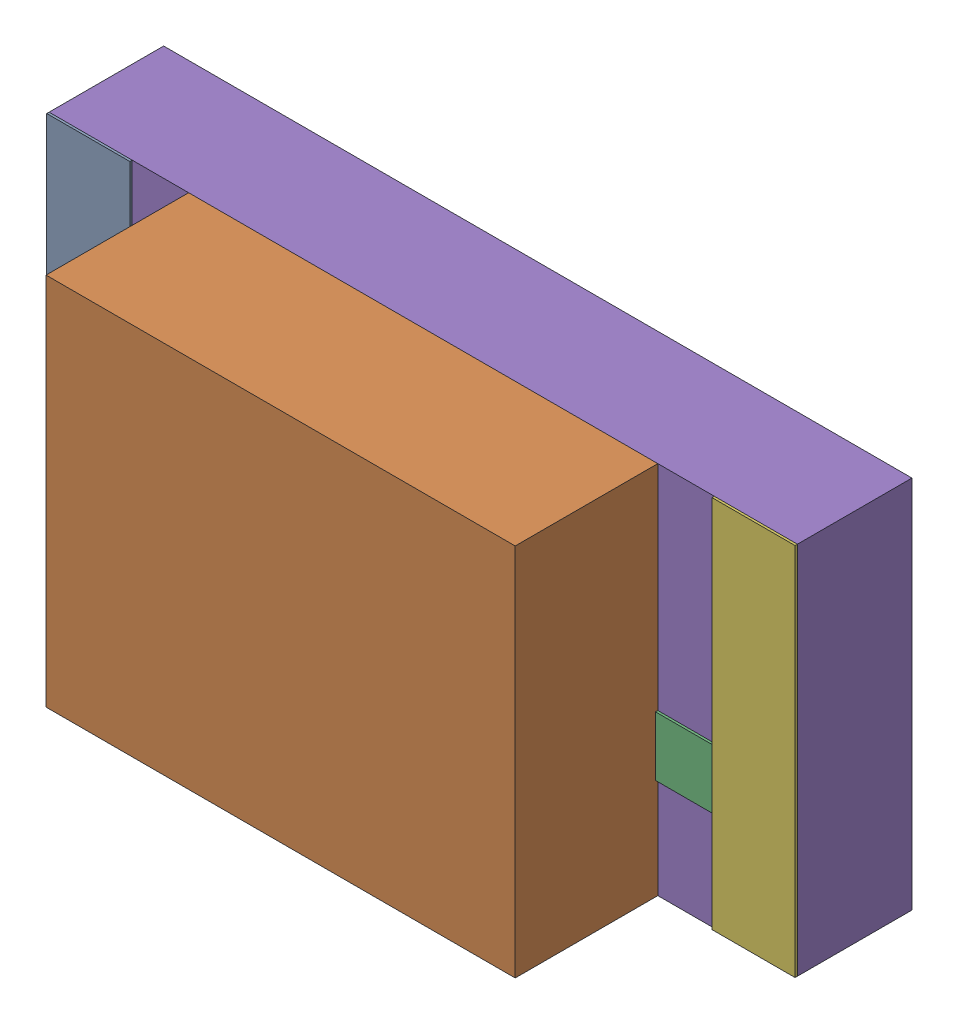
SolidWorks assembly SW3dPS-LED1206Y_Open_CASCADE_STEP_translator_6.2_294.2, configuration Défaut. Lengths in mm.
Overall size (3.2 1.6 1.1).
12 component instances, 5 part files, 0 mates.
Components (placement in the parent):
- SW3dPS-LED1206Y_352697808-1: SW3dPS-LED1206Y_352697808 [Défaut] at (0.1016 0.0127 0.5027) size (0.36 1.6 0.01)
  - SW3dPS-LED1206Y_Extruded2-1: SW3dPS-LED1206Y_Extruded2 [Défaut] at origin size (0.36 1.6 0.01)
- SW3dPS-LED1206Y_352697680-1: SW3dPS-LED1206Y_352697680 [Défaut] at (1.524 0.0127 0.5027) size (2.01 1.6 0.61)
  - SW3dPS-LED1206Y_Extruded4-1: SW3dPS-LED1206Y_Extruded4 [Défaut] at origin size (2.01 1.6 0.61)
- SW3dPS-LED1206Y_352698192-1: SW3dPS-LED1206Y_352698192 [Défaut] at (2.1971 0.0254 0.5027) size (1.14 0.76 0.01)
  - SW3dPS-LED1206Y_Extruded3-1: SW3dPS-LED1206Y_Extruded3 [Défaut] at origin size (1.14 0.76 0.01)
- SW3dPS-LED1206Y_352699472-1: SW3dPS-LED1206Y_352699472 [Défaut] at (0.6096 0.0254 0.5027) size (0.65 0.76 0.01)
  - SW3dPS-LED1206Y_Extruded-1: SW3dPS-LED1206Y_Extruded [Défaut] at origin size (0.65 0.76 0.01)
- SW3dPS-LED1206Y_352697936-1: SW3dPS-LED1206Y_352697936 [Défaut] at (1.524 0.0127 0.0127) size (3.2 1.6 0.49)
  - SW3dPS-LED1206Y_Extruded1-1: SW3dPS-LED1206Y_Extruded1 [Défaut] at origin size (3.2 1.6 0.49)
- SW3dPS-LED1206Y_352697808-2: SW3dPS-LED1206Y_352697808 [Défaut] at (2.9464 0.0127 0.5027) size (0.36 1.6 0.01)
  - SW3dPS-LED1206Y_Extruded2-1: SW3dPS-LED1206Y_Extruded2 [Défaut] at origin size (0.36 1.6 0.01)
